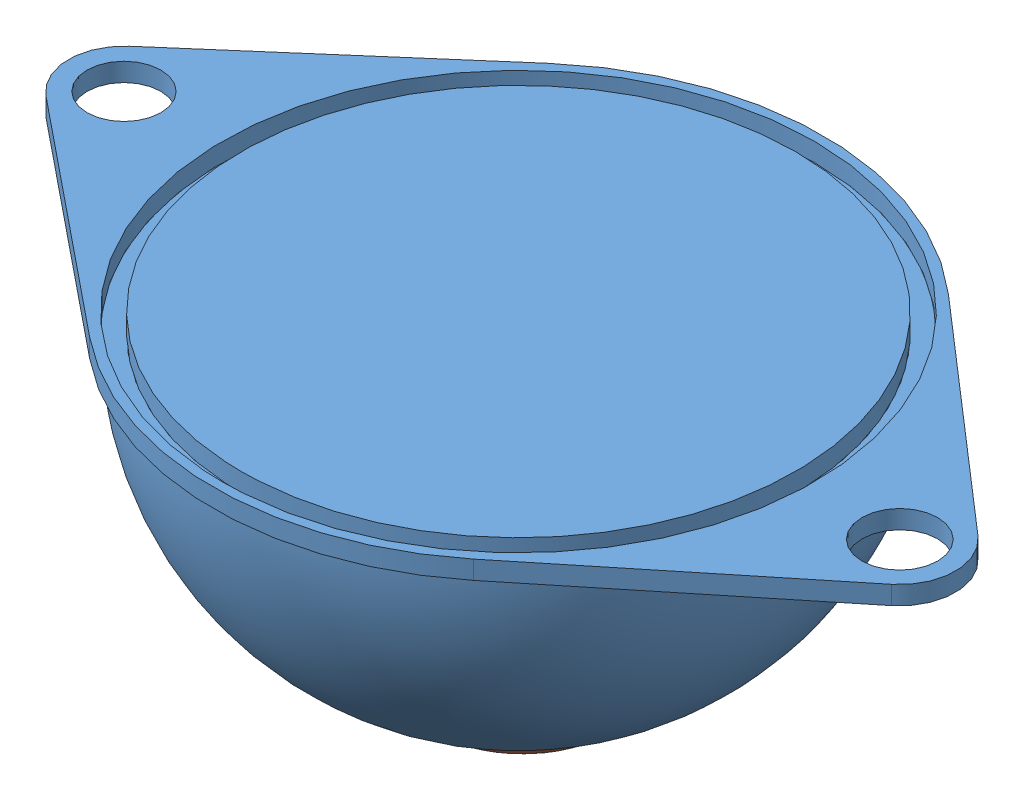
SolidWorks assembly free caster wheel, configuration Default. Lengths in mm.
Overall size (24 11.01 16.5).
2 component instances, 2 part files, 1 mates.
Components (placement in the parent):
- Part7-1: Part7 [Default] at (19.6841 32.5402 35.2847) size (24 7.57 16.5)
- Part8-1: Part8 [Default] at (20.2253 27.4514 35.9659) x (0.240879 -0.932599 -0.268767) z (0.797976 0.347931 -0.492116) size (8 8 8)
Mates (geometry in assembly coordinates):
- Distance1: distance = 1 mm: sphere of assembly; plane of assembly; sphere of Part8-1; plane of Part7-1 through (19.6841 32.5402 35.2847) normal (0 -1 0)
